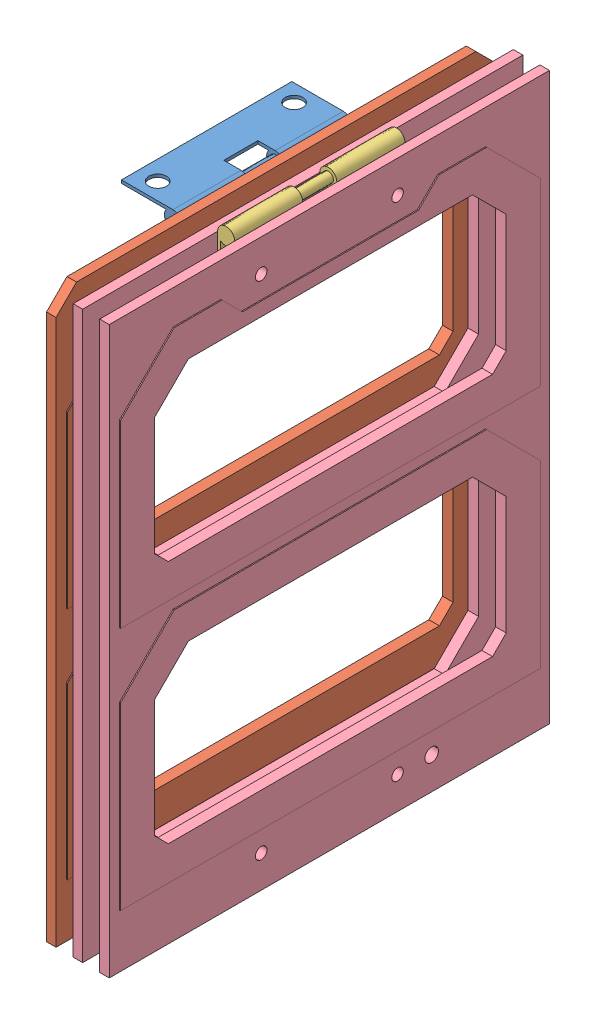
SolidWorks assembly COTS_CLOSED, configuration Default. Lengths in mm.
Overall size (23.06 108.61 82).
6 component instances, 4 part files, 15 mates.
Components (placement in the parent):
- COTS_STS1114_90-1: COTS_STS1114_90 [Default] at (8.5663 23.9515 10.0426) size (11.18 11.18 31.75)
- SP_Imperial_COTS_Hinge_BASE-1: SP_Imperial_COTS_Hinge_BASE [Default] at (10.1538 -26.5056 25.9176) x (0 1 0) z (1 0 0) size (105.41 82 1.98)
- COTS_STS1114_0-1: COTS_STS1114_0 [Default] at (13.5193 -79.2233 41.7926) x (1 0 0) z (0 0 -1) size (3.17 11.18 31.75)
- Solar_Panel_FULL_Imperial_COTS_Hinge-1: Solar_Panel_FULL_Imperial_COTS_Hinge [Default] at (16.8848 -26.5056 25.9176) x (0 -1 0) z (-1 0 0) size (105.41 82 1.98)
- COTS_STS1114_0-2: COTS_STS1114_0 [Default] at (18.4723 26.2121 10.0426) size (3.17 11.18 31.75)
- Solar_Panel_FULL_Imperial_COTS_Hinge-2: Solar_Panel_FULL_Imperial_COTS_Hinge [Default] at (20.0598 -26.5056 25.9176) x (0 1 0) z (1 0 0) size (105.41 82 1.98)
Mates (geometry in assembly coordinates):
- Coincident1: coincident anti-aligned: plane of COTS_STS1114_90-1 through (10.1538 23.9515 41.7926) normal (1 0 0); plane of SP_Imperial_COTS_Hinge_BASE-1 through (10.1538 -26.5056 25.9176) normal (-1 0 0)
- Concentric1: concentric aligned: circle of COTS_STS1114_90-1; circle of SP_Imperial_COTS_Hinge_BASE-1
- Parallel1: parallel anti-aligned: line of COTS_STS1114_90-1 through (10.1538 14.363 41.7926) axis (0 0 -1); line of SP_Imperial_COTS_Hinge_BASE-1 through (11.9318 26.1994 -11.2724) axis (0 0 1)
- Concentric2: concentric aligned: circle of SP_Imperial_COTS_Hinge_BASE-1; circle of COTS_STS1114_0-1
- Coincident3: coincident anti-aligned: plane of SP_Imperial_COTS_Hinge_BASE-1 through (11.9318 -26.5056 25.9176) normal (1 0 0); plane of COTS_STS1114_0-1 through (11.9318 -79.2233 10.0426) normal (-1 0 0)
- Parallel2: parallel aligned: line of SP_Imperial_COTS_Hinge_BASE-1 through (10.1538 -79.2106 -15.0824) axis (0 0 1); line of COTS_STS1114_0-1 through (11.9318 -69.6348 10.0426) axis (0 0 1)
- Coincident7: coincident anti-aligned: plane of COTS_STS1114_0-1 through (15.1068 -79.2233 10.0426) normal (1 0 0); plane of Solar_Panel_FULL_Imperial_COTS_Hinge-1 through (15.1068 -26.5056 25.9176) normal (-1 0 0)
- Concentric3: concentric anti-aligned: circle of COTS_STS1114_0-1; circle of Solar_Panel_FULL_Imperial_COTS_Hinge-1
- Parallel4: parallel aligned: line of COTS_STS1114_0-1 through (15.1068 -69.6348 10.0426) axis (0 0 1); line of Solar_Panel_FULL_Imperial_COTS_Hinge-1 through (16.8848 -79.2106 -15.0824) axis (0 0 1)
- Coincident9: coincident anti-aligned: plane of Solar_Panel_FULL_Imperial_COTS_Hinge-1 through (16.8848 -26.5056 25.9176) normal (1 0 0); plane of COTS_STS1114_0-2 through (16.8848 26.2121 41.7926) normal (-1 0 0)
- Concentric4: concentric aligned: cylinder of Solar_Panel_FULL_Imperial_COTS_Hinge-1 through (15.1068 20.205 38.6176) axis (1 0 0) radius 1.0795; circle of COTS_STS1114_0-2
- Parallel5: parallel anti-aligned: line of Solar_Panel_FULL_Imperial_COTS_Hinge-1 through (16.8848 26.1994 -15.0824) axis (0 0 1); line of COTS_STS1114_0-2 through (17.4436 16.6236 41.7926) axis (0 0 -1)
- Coincident11: coincident anti-aligned: plane of COTS_STS1114_0-2 through (20.0598 26.2121 41.7926) normal (1 0 0); plane of Solar_Panel_FULL_Imperial_COTS_Hinge-2 through (20.0598 -26.5056 25.9176) normal (-1 0 0)
- Concentric5: concentric anti-aligned: circle of COTS_STS1114_0-2; cylinder of Solar_Panel_FULL_Imperial_COTS_Hinge-2 through (21.8378 20.205 38.6176) axis (-1 0 0) radius 1.0795
- Parallel6: parallel anti-aligned: line of COTS_STS1114_0-2 through (20.0598 16.6236 41.7926) axis (0 0 -1); line of Solar_Panel_FULL_Imperial_COTS_Hinge-2 through (21.8378 26.1994 -15.0824) axis (0 0 1)
